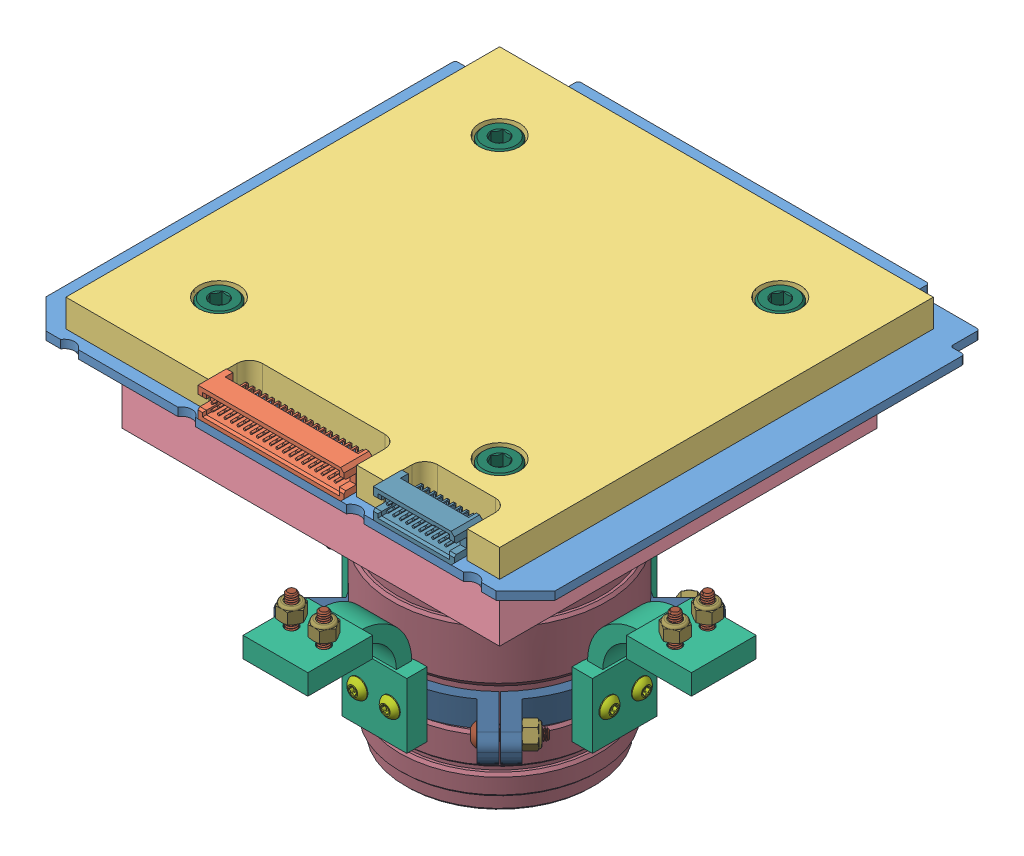
SolidWorks assembly CFCCard, configuration Default. Lengths in mm.
Overall size (99.8 74.52 107.17).
60 component instances, 15 part files, 63 mates.
Components (placement in the parent):
- CFCcard-1: CFCcard [Default] at (-25.7879 11.5524 2.0236) size (99.8 1.6 107.17)
- TFM_120_01_L_D_RA_defeature-1: TFM_120_01_L_D_RA_defeature [Default] at (-25.7879 15.2099 41.2606) x (1 0 0) z (0 -1 0) size (28.58 7.49 7.62)
- CoolerNarrowHoles-1: CoolerNarrowHoles [Default] at (-25.7879 17.7524 2.0236) x (1 0 0) z (0 0 -1) size (85 7 85)
- lensmount-2: lensmount [NarrowHoles] at (-25.7879 10.7524 2.0236) x (1 0 0) z (0 0 -1) size (74 24.21 80)
- detector-1: detector [Default] at (-25.7879 50.6812 2.0236) x (0 0 -1) z (0 -1 0) size (46.74 49.53 14.25)
- thermotivestrap-1: thermotivestrap [Default] at (-48.8688 -24.5936 2.0236) x (0 -1 0) z (1 0 0) size (23.4 12.7 23.4)
- 90910A921_LOW-PROFILE BUTTON HEAD TORX MACHINE SCREW-1: 90910A921_LOW-PROFILE BUTTON HEAD TORX MACHINE SCREW [90910A921] at (-48.2669 8.3824 12.1836) x (0 0 1) z (0 -1 0) size (3.8 3.8 6.11)
- 90910A921_LOW-PROFILE BUTTON HEAD TORX MACHINE SCREW-2: 90910A921_LOW-PROFILE BUTTON HEAD TORX MACHINE SCREW [90910A921] at (-48.2669 8.3824 -8.1364) x (0 0 1) z (0 -1 0) size (3.8 3.8 6.11)
- 90910A921_LOW-PROFILE BUTTON HEAD TORX MACHINE SCREW-3: 90910A921_LOW-PROFILE BUTTON HEAD TORX MACHINE SCREW [90910A921] at (-3.3089 8.3824 -8.1364) x (0 0 -1) z (0 -1 0) size (3.8 3.8 6.11)
- 90910A921_LOW-PROFILE BUTTON HEAD TORX MACHINE SCREW-4: 90910A921_LOW-PROFILE BUTTON HEAD TORX MACHINE SCREW [90910A921] at (-3.3089 8.3824 12.1836) x (0 0 -1) z (0 -1 0) size (3.8 3.8 6.11)
- 91828A111_TYPE 18-8 STAINLESS STEEL HEX NUT-1: 91828A111_TYPE 18-8 STAINLESS STEEL HEX NUT [91828A111] at (-3.3089 13.1524 -8.1364) x (1 0 0) z (0 1 0) size (4 4.62 1.83)
- 91828A111_TYPE 18-8 STAINLESS STEEL HEX NUT-2: 91828A111_TYPE 18-8 STAINLESS STEEL HEX NUT [91828A111] at (-3.3089 13.1524 12.1836) x (1 0 0) z (0 1 0) size (4 4.62 1.83)
- 91828A111_TYPE 18-8 STAINLESS STEEL HEX NUT-3: 91828A111_TYPE 18-8 STAINLESS STEEL HEX NUT [91828A111] at (-48.2669 13.1524 -8.1364) x (-1 0 0) z (0 1 0) size (4 4.62 1.83)
- 91828A111_TYPE 18-8 STAINLESS STEEL HEX NUT-4: 91828A111_TYPE 18-8 STAINLESS STEEL HEX NUT [91828A111] at (-48.2669 13.1524 12.1836) x (-1 0 0) z (0 1 0) size (4 4.62 1.83)
- Filter_Mount-1: Filter_Mount [Default] at (-25.7879 2.8624 2.0236) x (1 0 0) z (0 0 -1) size (45 3 40)
- strapclamp-1: strapclamp [Default] at (-25.7879 -37.8976 2.0236) x (0.707107 0 -0.707107) z (0.707107 0 0.707107) size (31.18 5 31.18)
- 92095A104_BUTTON HEAD HEX DRIVE SCREW-6: 92095A104_BUTTON HEAD HEX DRIVE SCREW [92095A104] at (-4.38 -37.8976 -13.7275) x (-0.353553 0.866025 0.353553) z (0.707107 0 0.707107) size (3.8 3.8 11.02)
- 93625A101_TYPE 18-8 STAINLESS STL NYLON-INSERT LOCKNUT-1: 93625A101_TYPE 18-8 STAINLESS STL NYLON-INSERT LOCKNUT [93625A101] at (-9.4004 -37.8976 -18.7479) x (0 1 0) z (-0.707107 0 0.707107) size (4 2.86 4.62)
- 92095A104_BUTTON HEAD HEX DRIVE SCREW-10: 92095A104_BUTTON HEAD HEX DRIVE SCREW [92095A104] at (-63.3788 -25.7476 -1.1514) x (-1 0 0) z (0 -1 0) size (3.8 3.8 11.02)
- 92095A104_BUTTON HEAD HEX DRIVE SCREW-11: 92095A104_BUTTON HEAD HEX DRIVE SCREW [92095A104] at (-63.3788 -25.7476 5.1986) x (-1 0 0) z (0 -1 0) size (3.8 3.8 11.02)
- 93625A101_TYPE 18-8 STAINLESS STL NYLON-INSERT LOCKNUT-5: 93625A101_TYPE 18-8 STAINLESS STL NYLON-INSERT LOCKNUT [93625A101] at (-63.3788 -19.2476 -1.1514) size (4 2.86 4.62)
- 93625A101_TYPE 18-8 STAINLESS STL NYLON-INSERT LOCKNUT-6: 93625A101_TYPE 18-8 STAINLESS STL NYLON-INSERT LOCKNUT [93625A101] at (-63.3788 -19.2476 5.1986) x (-1 0 0) z (0 0 -1) size (4 2.86 4.62)
- 90910A921_LOW-PROFILE BUTTON HEAD TORX MACHINE SCREW-5: 90910A921_LOW-PROFILE BUTTON HEAD TORX MACHINE SCREW [90910A921] at (-51.4288 -37.8976 -1.1514) x (0 1 0) z (-1 0 0) size (3.8 3.8 6.11)
- 90910A921_LOW-PROFILE BUTTON HEAD TORX MACHINE SCREW-6: 90910A921_LOW-PROFILE BUTTON HEAD TORX MACHINE SCREW [90910A921] at (-51.4288 -37.8976 5.1986) x (0 1 0) z (-1 0 0) size (3.8 3.8 6.11)
- CFClens-2: CFClens [Default] at (-25.7879 -56.4538 2.0236) x (-0.819413 0 0.573204) z (0.573204 0 0.819413) size (45.15 60.78 42)
- thermotivestrap-8: thermotivestrap [Default] at (-25.7879 -24.5936 25.1044) x (0 -1 0) z (0 0 -1) size (23.4 12.7 23.4)
- thermotivestrap-9: thermotivestrap [Default] at (-2.707 -24.5936 2.0236) x (0 -1 0) z (-1 0 0) size (23.4 12.7 23.4)
- thermotivestrap-10: thermotivestrap [Default] at (-25.7879 -24.5936 -21.0573) x (0 -1 0) z (0 0 1) size (23.4 12.7 23.4)
- strapclamp-7: strapclamp [Default] at (-25.7879 -37.8976 2.0236) x (-0.707107 0 -0.707107) z (0.707107 0 -0.707107) size (31.18 5 31.18)
- strapclamp-8: strapclamp [Default] at (-25.7879 -37.8976 2.0236) x (-0.707107 0 0.707107) z (-0.707107 0 -0.707107) size (31.18 5 31.18)
- strapclamp-9: strapclamp [Default] at (-25.7879 -37.8976 2.0236) x (0.707107 0 0.707107) z (-0.707107 0 0.707107) size (31.18 5 31.18)
- 93625A101_TYPE 18-8 STAINLESS STL NYLON-INSERT LOCKNUT-13: 93625A101_TYPE 18-8 STAINLESS STL NYLON-INSERT LOCKNUT [93625A101] at (-46.5594 -37.8976 -14.3639) x (0 1 0) z (0.707107 0 0.707107) size (4 2.86 4.62)
- 93625A101_TYPE 18-8 STAINLESS STL NYLON-INSERT LOCKNUT-14: 93625A101_TYPE 18-8 STAINLESS STL NYLON-INSERT LOCKNUT [93625A101] at (-42.1753 -37.8976 22.7951) x (0 1 0) z (0.707107 0 -0.707107) size (4 2.86 4.62)
- 93625A101_TYPE 18-8 STAINLESS STL NYLON-INSERT LOCKNUT-15: 93625A101_TYPE 18-8 STAINLESS STL NYLON-INSERT LOCKNUT [93625A101] at (-5.0164 -37.8976 18.411) x (0 1 0) z (-0.707107 0 -0.707107) size (4 2.86 4.62)
- 92095A104_BUTTON HEAD HEX DRIVE SCREW-18: 92095A104_BUTTON HEAD HEX DRIVE SCREW [92095A104] at (-41.5389 -37.8976 -19.3843) x (0.353553 0.866025 0.353553) z (0.707107 0 -0.707107) size (3.8 3.8 11.02)
- 92095A104_BUTTON HEAD HEX DRIVE SCREW-19: 92095A104_BUTTON HEAD HEX DRIVE SCREW [92095A104] at (-47.1958 -37.8976 17.7746) x (0.353553 0.866025 -0.353553) z (-0.707107 0 -0.707107) size (3.8 3.8 11.02)
- 92095A104_BUTTON HEAD HEX DRIVE SCREW-20: 92095A104_BUTTON HEAD HEX DRIVE SCREW [92095A104] at (-10.0368 -37.8976 23.4315) x (-0.353553 0.866025 -0.353553) z (-0.707107 0 0.707107) size (3.8 3.8 11.02)
- 90910A921_LOW-PROFILE BUTTON HEAD TORX MACHINE SCREW-13: 90910A921_LOW-PROFILE BUTTON HEAD TORX MACHINE SCREW [90910A921] at (-28.9629 -37.8976 27.6644) x (0 1 0) z (0 0 1) size (3.8 3.8 6.11)
- 90910A921_LOW-PROFILE BUTTON HEAD TORX MACHINE SCREW-14: 90910A921_LOW-PROFILE BUTTON HEAD TORX MACHINE SCREW [90910A921] at (-0.147 -37.8976 5.1986) x (0 1 0) z (1 0 0) size (3.8 3.8 6.11)
- 90910A921_LOW-PROFILE BUTTON HEAD TORX MACHINE SCREW-15: 90910A921_LOW-PROFILE BUTTON HEAD TORX MACHINE SCREW [90910A921] at (-22.6129 -37.8976 -23.6173) x (0 1 0) z (0 0 -1) size (3.8 3.8 6.11)
- 90910A921_LOW-PROFILE BUTTON HEAD TORX MACHINE SCREW-16: 90910A921_LOW-PROFILE BUTTON HEAD TORX MACHINE SCREW [90910A921] at (-22.6129 -37.8976 27.6644) x (0 1 0) z (0 0 1) size (3.8 3.8 6.11)
- 90910A921_LOW-PROFILE BUTTON HEAD TORX MACHINE SCREW-17: 90910A921_LOW-PROFILE BUTTON HEAD TORX MACHINE SCREW [90910A921] at (-0.147 -37.8976 -1.1514) x (0 1 0) z (1 0 0) size (3.8 3.8 6.11)
- 90910A921_LOW-PROFILE BUTTON HEAD TORX MACHINE SCREW-18: 90910A921_LOW-PROFILE BUTTON HEAD TORX MACHINE SCREW [90910A921] at (-28.9629 -37.8976 -23.6173) x (0 1 0) z (0 0 -1) size (3.8 3.8 6.11)
- 92095A104_BUTTON HEAD HEX DRIVE SCREW-21: 92095A104_BUTTON HEAD HEX DRIVE SCREW [92095A104] at (-22.6129 -25.7476 39.6144) x (0 0 1) z (0 -1 0) size (3.8 3.8 11.02)
- 92095A104_BUTTON HEAD HEX DRIVE SCREW-22: 92095A104_BUTTON HEAD HEX DRIVE SCREW [92095A104] at (11.803 -25.7476 -1.1514) x (1 0 0) z (0 -1 0) size (3.8 3.8 11.02)
- 92095A104_BUTTON HEAD HEX DRIVE SCREW-23: 92095A104_BUTTON HEAD HEX DRIVE SCREW [92095A104] at (-28.9629 -25.7476 -35.5673) x (0 0 -1) z (0 -1 0) size (3.8 3.8 11.02)
- 92095A104_BUTTON HEAD HEX DRIVE SCREW-24: 92095A104_BUTTON HEAD HEX DRIVE SCREW [92095A104] at (-28.9629 -25.7476 39.6144) x (0 0 1) z (0 -1 0) size (3.8 3.8 11.02)
- 92095A104_BUTTON HEAD HEX DRIVE SCREW-25: 92095A104_BUTTON HEAD HEX DRIVE SCREW [92095A104] at (11.803 -25.7476 5.1986) x (1 0 0) z (0 -1 0) size (3.8 3.8 11.02)
- 92095A104_BUTTON HEAD HEX DRIVE SCREW-26: 92095A104_BUTTON HEAD HEX DRIVE SCREW [92095A104] at (-22.6129 -25.7476 -35.5673) x (0 0 -1) z (0 -1 0) size (3.8 3.8 11.02)
- 93625A101_TYPE 18-8 STAINLESS STL NYLON-INSERT LOCKNUT-16: 93625A101_TYPE 18-8 STAINLESS STL NYLON-INSERT LOCKNUT [93625A101] at (-22.6129 -19.2476 39.6144) x (0 0 1) z (-1 0 0) size (4 2.86 4.62)
- 93625A101_TYPE 18-8 STAINLESS STL NYLON-INSERT LOCKNUT-17: 93625A101_TYPE 18-8 STAINLESS STL NYLON-INSERT LOCKNUT [93625A101] at (11.803 -19.2476 -1.1514) size (4 2.86 4.62)
- 93625A101_TYPE 18-8 STAINLESS STL NYLON-INSERT LOCKNUT-18: 93625A101_TYPE 18-8 STAINLESS STL NYLON-INSERT LOCKNUT [93625A101] at (-28.9629 -19.2476 -35.5673) x (0 0 -1) z (1 0 0) size (4 2.86 4.62)
- 93625A101_TYPE 18-8 STAINLESS STL NYLON-INSERT LOCKNUT-19: 93625A101_TYPE 18-8 STAINLESS STL NYLON-INSERT LOCKNUT [93625A101] at (-28.9629 -19.2476 39.6144) x (0 0 -1) z (1 0 0) size (4 2.86 4.62)
- 93625A101_TYPE 18-8 STAINLESS STL NYLON-INSERT LOCKNUT-20: 93625A101_TYPE 18-8 STAINLESS STL NYLON-INSERT LOCKNUT [93625A101] at (11.803 -19.2476 5.1986) x (-1 0 0) z (0 0 -1) size (4 2.86 4.62)
- 93625A101_TYPE 18-8 STAINLESS STL NYLON-INSERT LOCKNUT-21: 93625A101_TYPE 18-8 STAINLESS STL NYLON-INSERT LOCKNUT [93625A101] at (-22.6129 -19.2476 -35.5673) x (0 0 1) z (-1 0 0) size (4 2.86 4.62)
- TFM_110_01_L_D_RA_defeature-1: TFM_110_01_L_D_RA_defeature [Default] at (2.2121 15.2099 41.2606) x (1 0 0) z (0 -1 0) size (15.88 7.49 7.62)
- 90037A112_METRIC HIGH-STRENGTH 316 SS SOCKET HEAD SCREW-1: 90037A112_METRIC HIGH-STRENGTH 316 SS SOCKET HEAD SCREW [90037A112] at (-53.2879 -0.4136 29.5236) x (0.866025 0 0.5) z (0 -1 0) size (7 7 18.79)
- 90037A112_METRIC HIGH-STRENGTH 316 SS SOCKET HEAD SCREW-2: 90037A112_METRIC HIGH-STRENGTH 316 SS SOCKET HEAD SCREW [90037A112] at (1.7121 -0.4136 29.5236) x (-0.866025 0 0.5) z (0 -1 0) size (7 7 18.79)
- 90037A112_METRIC HIGH-STRENGTH 316 SS SOCKET HEAD SCREW-3: 90037A112_METRIC HIGH-STRENGTH 316 SS SOCKET HEAD SCREW [90037A112] at (-53.2879 -0.4136 -25.4764) x (0.866025 0 -0.5) z (0 -1 0) size (7 7 18.79)
- 90037A112_METRIC HIGH-STRENGTH 316 SS SOCKET HEAD SCREW-4: 90037A112_METRIC HIGH-STRENGTH 316 SS SOCKET HEAD SCREW [90037A112] at (1.7121 -0.4136 -25.4764) x (-0.866025 0 -0.5) z (0 -1 0) size (7 7 18.79)
Mates (geometry in assembly coordinates):
- Coincident1: coincident anti-aligned: plane of CFCcard-1 through (-25.7879 12.3524 2.0236) normal (0 1 0); plane of TFM_120_01_L_D_RA_defeature-1 through (-40.0754 12.3524 46.8486) normal (0 -1 0)
- Coincident2: coincident: line of CFCcard-1 through (24.1121 12.3524 39.3556) axis (-1 0 0); plane of TFM_120_01_L_D_RA_defeature-1 through (-25.7879 15.2099 39.3556) normal (0 0 -1)
- Coincident3: coincident: line of CFCcard-1 through (-25.7879 12.3524 -3.2046) axis (0 0 1); plane of TFM_120_01_L_D_RA_defeature-1 through (-25.7879 15.2099 41.2606) normal (1 0 0)
- Coincident4: coincident aligned: plane of CFCcard-1 through (-25.7879 11.5524 2.0236) normal (1 0 0); plane of CoolerNarrowHoles-1 through (-25.7879 17.7524 2.0236) normal (1 0 0)
- Coincident5: coincident anti-aligned: plane of CFCcard-1 through (-25.7879 11.5524 2.0236) normal (0 0 1); plane of CoolerNarrowHoles-1 through (-25.7879 17.7524 2.0236) normal (0 0 -1)
- Concentric2: concentric: circle of CFCcard-1; circle of lensmount-2
- Coincident8: coincident aligned: plane of CFCcard-1 through (-25.7879 11.5524 2.0236) normal (1 0 0); plane of detector-1 through (-25.7879 50.6812 2.0236) normal (1 0 0)
- Coincident10: coincident anti-aligned: plane of CFCcard-1 through (-25.7879 11.5524 2.0236) normal (0 0 1); plane of detector-1 through (-25.7879 50.6812 2.0236) normal (0 0 -1)
- Coincident13: coincident: point of CFCcard-1; plane of CFClens-1 through (-25.7879 -56.4538 2.0236) normal (0.712652 0 -0.701517)
- Coincident14: coincident anti-aligned: plane of CFCcard-1 through (-25.7879 10.7524 2.0236) normal (0 -1 0); plane of lensmount-2 through (-65.7879 10.7524 2.0236) normal (0 1 0)
- Coincident15: coincident anti-aligned: plane of CFCcard-1 through (-25.7879 12.3524 2.0236) normal (0 1 0); plane of CoolerNarrowHoles-1 through (-25.7879 12.3524 2.0236) normal (0 -1 0)
- Parallel1: parallel: line of CFCcard-1 through (24.1121 12.3524 41.0236) axis (0 0 -1); plane of lensmount-2 through (11.2121 10.7524 -34.9764) normal (1 0 0)
- Coincident18: coincident anti-aligned: plane of CFCcard-1 through (-25.7879 10.7524 2.0236) normal (0 -1 0); plane of detector-1 through (-25.7879 10.7524 2.0236) normal (0 1 0)
- Concentric5: concentric aligned: circle of CFCcard-1; circle of CFClens-1
- Concentric6: concentric anti-aligned: circle of CFCcard-1; circle of lensmount-2
- Concentric8: concentric anti-aligned: circle of detector-1; circle of 90910A921_LOW-PROFILE BUTTON HEAD TORX MACHINE SCREW-1
- Coincident21: coincident anti-aligned: plane of detector-1 through (-25.7879 9.4824 2.0236) normal (0 -1 0); plane of 90910A921_LOW-PROFILE BUTTON HEAD TORX MACHINE SCREW-1 through (-46.3669 9.4824 12.1836) normal (0 1 0)
- Parallel4: parallel aligned: plane of detector-1 through (-50.5529 10.7524 19.8036) normal (-1 0 0); plane of 90910A921_LOW-PROFILE BUTTON HEAD TORX MACHINE SCREW-1 through (-48.2669 8.3824 12.1836) normal (-1 0 0)
- Coincident22: coincident anti-aligned: plane of CFCcard-1 through (-25.7879 12.3524 2.0236) normal (0 1 0); plane of 91828A111_TYPE 18-8 STAINLESS STEEL HEX NUT-1 through (-5.3089 12.3524 -9.2911) normal (0 -1 0)
- Concentric9: concentric aligned: circle of CFCcard-1; circle of 94150A114_316 STAINLESS STEEL HEX NUT-1
- Parallel5: parallel aligned: plane of CFCcard-1 through (24.1121 10.7524 2.0236) normal (1 0 0); plane of 91828A111_TYPE 18-8 STAINLESS STEEL HEX NUT-1 through (-1.3089 13.9524 -6.9817) normal (1 0 0)
- Coincident23: coincident aligned: plane of detector-1 through (-25.7879 50.6812 2.0236) normal (1 0 0); plane of Filter_Mount-1 through (-25.7879 2.8624 2.0236) normal (1 0 0)
- Coincident24: coincident aligned: plane of detector-1 through (-25.7879 50.6812 2.0236) normal (0 0 -1); plane of Filter_Mount-1 through (-25.7879 2.8624 2.0236) normal (0 0 -1)
- Coincident25: coincident anti-aligned: plane of detector-1 through (-25.7879 1.8624 2.0236) normal (0 -1 0); plane of Filter_Mount-1 through (-25.7879 1.8624 2.0236) normal (0 1 0)
- Coincident26: coincident anti-aligned: plane of lensmount-2 through (-25.7879 -13.4538 2.0236) normal (0 -1 0); plane of CFClens-1 through (-15.0324 -13.4538 -8.5639) normal (0 1 0)
- Concentric10: concentric aligned: cylinder of CFClens-1 through (-25.7879 -37.9538 2.0236) axis (0 -1 0) radius 19.5; cylinder of strapclamp-1 through (-25.7879 -35.3976 2.0236) axis (0 -1 0) radius 19.5
- Coincident28: coincident: line of lensmount-2 through (-62.7879 10.7524 -34.9764) axis (0 -1 0); plane of strapclamp-1 through (-25.7879 -37.8976 2.0236) normal (0.707107 0 -0.707107)
- Concentric17: concentric anti-aligned: circle of 90910A923_LOW-PROFILE BUTTON HEAD TORX MACHINE SCREW-5; circle of 93625A101_TYPE 18-8 STAINLESS STL NYLON-INSERT LOCKNUT-1
- Distance3: distance = 0.6 mm aligned: plane of thermalstraps-1 through (-25.7879 -40.8538 -20.9764) normal (0 -1 0); plane of CFClens-1 through (-12.2475 -41.4538 -11.3053) normal (0 -1 0)
- Coincident34: coincident anti-aligned: plane of thermotivestrap-1 through (-46.3288 -31.5476 -1.7864) normal (1 0 0); plane of strapclamp-1 through (-46.3288 -35.3976 8.3736) normal (-1 0 0)
- Coincident36: coincident aligned: plane of lensmount-2 through (-25.7879 10.7524 2.0236) normal (0 0 -1); plane of thermotivestrap-1 through (-48.8688 -24.5936 2.0236) normal (0 0 -1)
- Distance5: distance = 16.35 mm anti-aligned: plane of thermotivestrap-1 through (-69.7288 -20.8476 -1.7864) normal (0 1 0); plane of lensmount-2 through (-25.7879 -4.4976 2.0236) normal (0 -1 0)
- Concentric18: concentric aligned: circle of 92095A104_BUTTON HEAD HEX DRIVE SCREW-10; circle of thermotivestrap-1
- Coincident37: coincident anti-aligned: plane of thermotivestrap-1 through (-69.7288 -24.8476 -1.7864) normal (0 -1 0); plane of 92095A104_BUTTON HEAD HEX DRIVE SCREW-10 through (-63.3788 -24.8476 0.7486) normal (0 1 0)
- Concentric19: concentric aligned: circle of thermotivestrap-1; circle of strapclamp-1
- Concentric20: concentric aligned: circle of thermotivestrap-1; circle of 92095A104_BUTTON HEAD HEX DRIVE SCREW-11
- Coincident38: coincident anti-aligned: plane of thermotivestrap-1 through (-69.7288 -24.8476 -1.7864) normal (0 -1 0); plane of 92095A104_BUTTON HEAD HEX DRIVE SCREW-11 through (-63.3788 -24.8476 7.0986) normal (0 1 0)
- Parallel12: parallel aligned: plane of thermotivestrap-1 through (-48.8688 -24.5936 -4.3264) normal (0 0 -1); plane of 92095A104_BUTTON HEAD HEX DRIVE SCREW-10 through (-63.3788 -25.7476 -1.1514) normal (0 0 -1)
- Parallel13: parallel aligned: plane of thermotivestrap-1 through (-48.8688 -24.5936 -4.3264) normal (0 0 -1); plane of 92095A104_BUTTON HEAD HEX DRIVE SCREW-11 through (-63.3788 -25.7476 5.1986) normal (0 0 -1)
- Concentric21: concentric aligned: circle of thermotivestrap-1; circle of 93625A101_TYPE 18-8 STAINLESS STL NYLON-INSERT LOCKNUT-5
- Parallel14: parallel aligned: plane of thermotivestrap-1 through (-69.7288 -20.8476 -1.7864) normal (-1 0 0); plane of 93625A101_TYPE 18-8 STAINLESS STL NYLON-INSERT LOCKNUT-5 through (-65.3788 -16.4476 -2.3061) normal (-1 0 0)
- Concentric22: concentric aligned: circle of thermotivestrap-1; circle of 93625A101_TYPE 18-8 STAINLESS STL NYLON-INSERT LOCKNUT-6
- Parallel15: parallel aligned: plane of thermotivestrap-1 through (-69.7288 -20.8476 -1.7864) normal (-1 0 0); plane of 93625A101_TYPE 18-8 STAINLESS STL NYLON-INSERT LOCKNUT-6 through (-65.3788 -16.4476 4.0439) normal (-1 0 0)
- Distance7: distance = 1.6 mm anti-aligned: plane of thermotivestrap-1 through (-69.7288 -20.8476 -1.7864) normal (0 1 0); plane of 93625A101_TYPE 18-8 STAINLESS STL NYLON-INSERT LOCKNUT-6 through (-61.3788 -19.2476 8.6627) normal (0 -1 0)
- Distance8: distance = 1.6 mm anti-aligned: plane of 93625A101_TYPE 18-8 STAINLESS STL NYLON-INSERT LOCKNUT-5 through (-65.3788 -19.2476 -4.6155) normal (0 -1 0); plane of thermotivestrap-1 through (-69.7288 -20.8476 -1.7864) normal (0 1 0)
- Concentric23: concentric aligned: circle of thermotivestrap-1; circle of 90910A921_LOW-PROFILE BUTTON HEAD TORX MACHINE SCREW-5
- Coincident41: coincident anti-aligned: plane of thermotivestrap-1 through (-50.3288 -31.5476 -1.7864) normal (-1 0 0); plane of 90910A921_LOW-PROFILE BUTTON HEAD TORX MACHINE SCREW-5 through (-50.3288 -37.8976 0.7486) normal (1 0 0)
- Concentric24: concentric aligned: circle of thermotivestrap-1; circle of 90910A921_LOW-PROFILE BUTTON HEAD TORX MACHINE SCREW-6
- Coincident42: coincident anti-aligned: plane of thermotivestrap-1 through (-50.3288 -31.5476 -1.7864) normal (-1 0 0); plane of 90910A921_LOW-PROFILE BUTTON HEAD TORX MACHINE SCREW-6 through (-50.3288 -37.8976 7.0986) normal (1 0 0)
- Parallel16: parallel aligned: plane of thermotivestrap-1 through (-48.8688 -24.5936 -4.3264) normal (0 0 -1); plane of 90910A921_LOW-PROFILE BUTTON HEAD TORX MACHINE SCREW-5 through (-51.4288 -37.8976 -1.1514) normal (0 0 -1)
- Parallel17: parallel aligned: plane of thermotivestrap-1 through (-48.8688 -24.5936 -4.3264) normal (0 0 -1); plane of 90910A921_LOW-PROFILE BUTTON HEAD TORX MACHINE SCREW-6 through (-51.4288 -37.8976 5.1986) normal (0 0 -1)
- Concentric25: concentric anti-aligned: circle of lensmount-2; circle of CFClens-2
- Coincident44: coincident anti-aligned: plane of lensmount-2 through (-25.7879 -13.4538 2.0236) normal (0 -1 0); plane of CFClens-2 through (-40.5373 -13.4538 12.3412) normal (0 1 0)
- Concentric26: concentric aligned: circle of 93625A101_TYPE 18-8 STAINLESS STL NYLON-INSERT LOCKNUT-1; circle of strapclamp-9
- Coincident45: coincident anti-aligned: plane of 93625A101_TYPE 18-8 STAINLESS STL NYLON-INSERT LOCKNUT-1 through (-6.951 -39.8976 -21.1974) normal (0.707107 0 0.707107); plane of strapclamp-9 through (-5.8649 -35.3976 -22.2835) normal (-0.707107 0 -0.707107)
- Parallel18: parallel aligned: plane of 93625A101_TYPE 18-8 STAINLESS STL NYLON-INSERT LOCKNUT-1 through (-9.4004 -37.8976 -18.7479) normal (0 1 0)
- Coincident47: coincident anti-aligned: plane of 92095A104_BUTTON HEAD HEX DRIVE SCREW-6 through (-3.8529 -36.9476 -15.5274) normal (-0.707107 0 -0.707107); plane of strapclamp-8 through (-8.5519 -35.3976 -10.8283) normal (0.707107 0 0.707107)
- Coincident48: coincident anti-aligned: plane of CFCcard-1 through (-25.7879 12.3524 2.0236) normal (0 1 0); plane of TFM_110_01_L_D_RA_defeature-1 through (-5.7254 12.3524 46.8486) normal (0 -1 0)
- Coincident49: coincident: line of CFCcard-1 through (2.2121 12.3524 50.6915) axis (0 0 -1); plane of TFM_110_01_L_D_RA_defeature-1 through (2.2121 15.2099 41.2606) normal (1 0 0)
- Coincident50: coincident: line of CFCcard-1 through (24.1121 12.3524 39.3556) axis (-1 0 0); plane of TFM_110_01_L_D_RA_defeature-1 through (2.2121 15.2099 39.3556) normal (0 0 -1)
- Coincident51: coincident anti-aligned: plane of CoolerNarrowHoles-1 through (-53.2879 13.5864 29.5236) normal (0 1 0); plane of 90037A112_METRIC HIGH-STRENGTH 316 SS SOCKET HEAD SCREW-1 through (-53.2879 13.5864 29.5236) normal (0 -1 0)
- Concentric27: concentric anti-aligned: cylinder of CoolerNarrowHoles-1 through (-53.2879 13.5864 29.5236) axis (0 1 0) radius 3.969; cylinder of 90037A112_METRIC HIGH-STRENGTH 316 SS SOCKET HEAD SCREW-1 through (-53.2879 17.5864 29.5236) axis (0 -1 0) radius 3.5
- Parallel19: parallel aligned: plane of CoolerNarrowHoles-1 through (-68.2879 12.3524 44.5236) normal (0 0 1); plane of 90037A112_METRIC HIGH-STRENGTH 316 SS SOCKET HEAD SCREW-1 through (-52.4219 15.3364 28.0236) normal (0 0 1)
